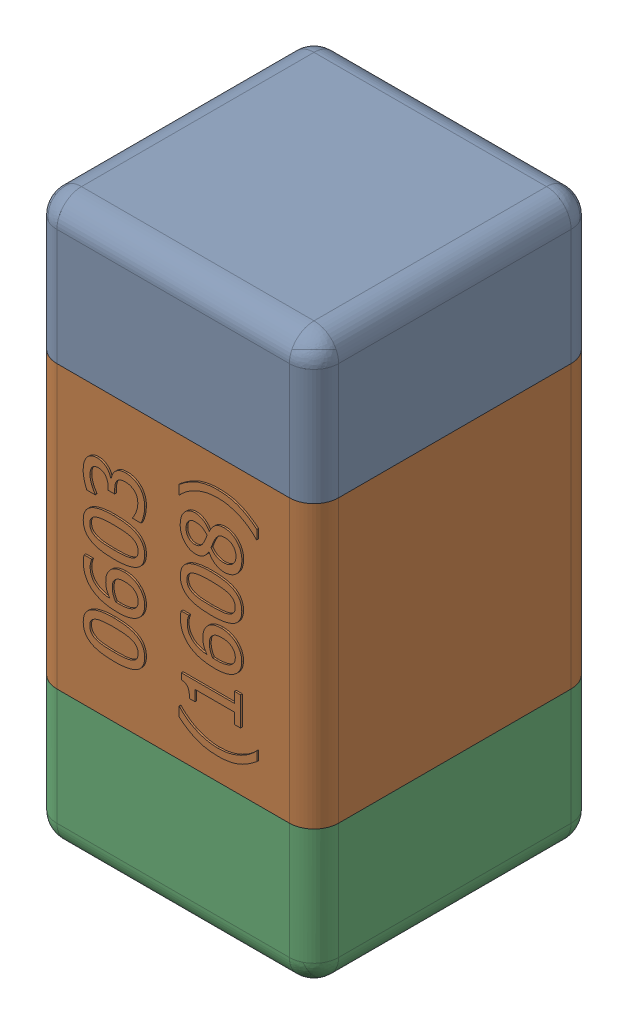
SolidWorks assembly C32, configuration Standard. Lengths in mm.
Overall size (0.81 1.61 0.81).
4 component instances, 3 part files, 0 mates.
Components (placement in the parent):
- C32-subassembly-1-1: C32-subassembly-1 [Standard] at (-14.4001 -1.4999 0) x (0 1 0) z (0 0 1) size (1.61 0.81 0.81)
  - User Library-0603_Cap-1: User Library-0603_Cap [Standard] at origin size (0.41 0.81 0.81)
  - User Library-0603_Cap-1-1: User Library-0603_Cap-1 [Standard] at origin size (0.8 0.8 0.81)
  - User Library-0603_Cap-2-1: User Library-0603_Cap-2 [Standard] at origin size (0.41 0.81 0.81)
